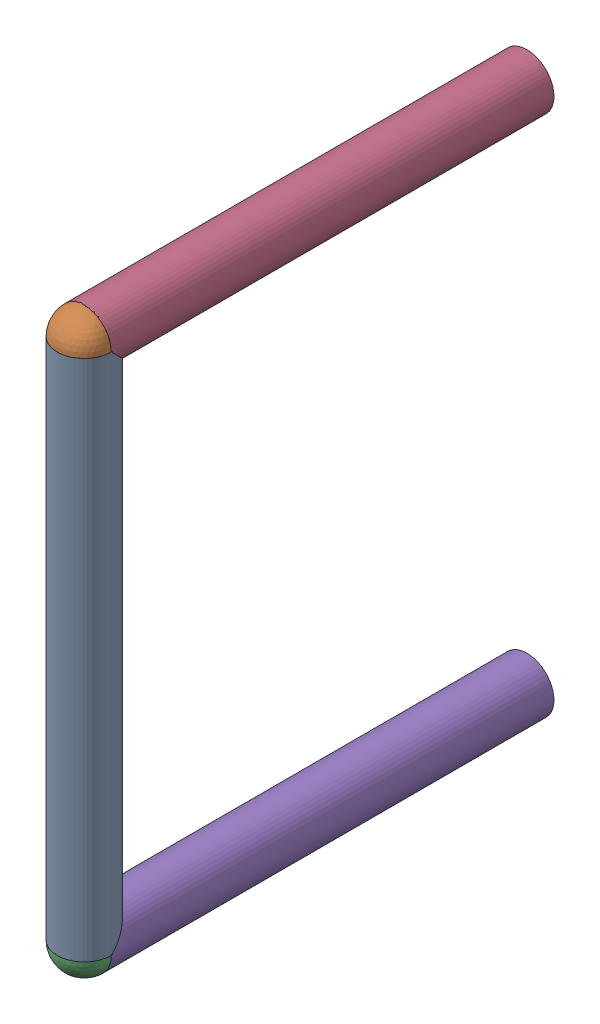
SolidWorks assembly TP10, configuration Default. Lengths in mm.
Overall size (1.05 11.21 9.13).
10 component instances, 3 part files, 0 mates.
Components (placement in the parent):
- 6575497552-1: 6575497552 [Default] at (54.3561 34.0359 6.105) x (0 0 -1) z (0 1 0) size (1.05 1.05 10.16)
  - Cylinder-1: Cylinder [Default] at origin size (1.05 1.05 10.16)
- 6575497312-1: 6575497312 [Default] at (54.3559 44.1961 6.105) x (0 1 0) z (0 0 1) size (1.05 1.05 1.05)
  - Sphere-1: Sphere [Default] at origin size (1.05 1.05 1.05)
- 6575497312-2: 6575497312 [Default] at (54.356 34.036 6.105) x (0 1 0) z (0 0 1) size (1.05 1.05 1.05)
  - Sphere-1: Sphere [Default] at origin size (1.05 1.05 1.05)
- 6575496992-1: 6575496992 [Default] at (54.3559 44.1961 -2.5) x (0 1 0) z (0 0 1) size (1.05 1.05 8.6)
  - Cylinder_2-1: Cylinder_2 [Default] at origin size (1.05 1.05 8.6)
- 6575496992-2: 6575496992 [Default] at (54.3559 34.0361 -2.5) x (0 1 0) z (0 0 1) size (1.05 1.05 8.6)
  - Cylinder_2-1: Cylinder_2 [Default] at origin size (1.05 1.05 8.6)
